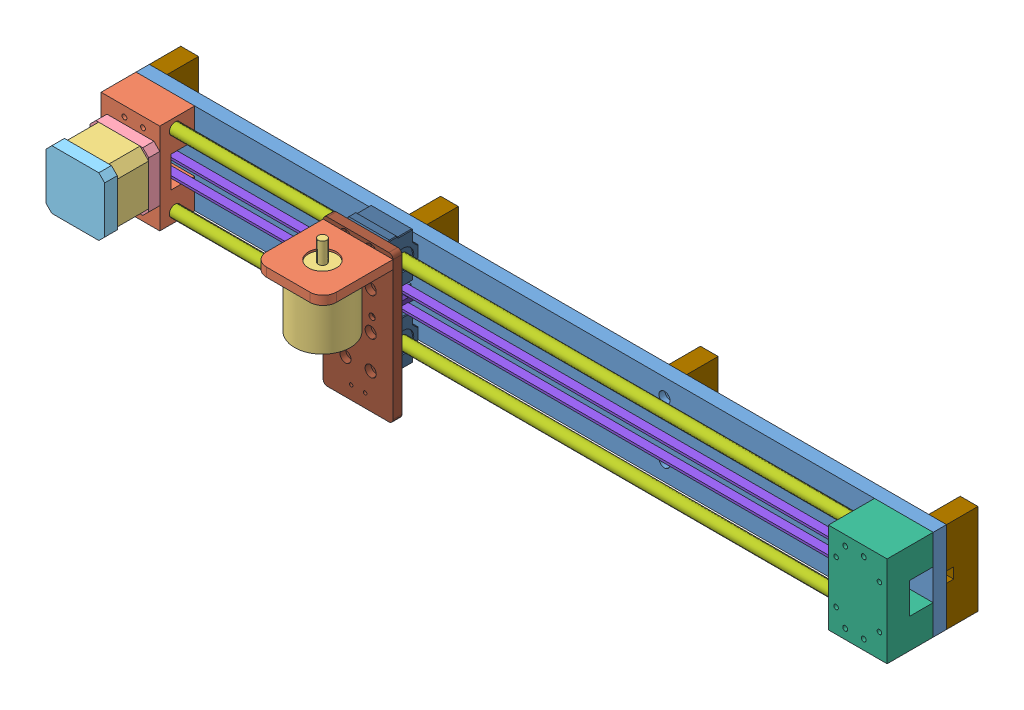
SolidWorks assembly Montagem, configuration Valor predeterminado. Lengths in mm.
Overall size (570.66 115.83 117).
38 component instances, 21 part files, 63 mates.
Components (placement in the parent):
- Base-1: Base [Valor predeterminado] at (-675.4212 -192.8927 563.7125) size (570.47 65 9.53)
- Apoio_guias-1: Apoio_guias [Valor predeterminado] at (-675.4212 -192.8927 573.2375) size (42 65 25)
- NEMA_17_STEPPER_ASSEMBLY-1: NEMA_17_STEPPER_ASSEMBLY [Valor predeterminado] at (-686.9212 389.0823 567.6436) x (0 1 0) z (0 0 1) size (42 42.19 62.3)
  - STEPPER_PART_2-1: STEPPER_PART_2 [Valor predeterminado] at (-549.475 -32.5 22.825) x (0 -1 0) z (0 0 1) size (42 42 22.3)
  - STEPPER_PART_3-1: STEPPER_PART_3 [Valor predeterminado] at (-549.475 -32.5 30.525) x (0 -1 0) z (0 0 1) size (42 42 31)
  - STEPPER_PART_1-1: STEPPER_PART_1 [Valor predeterminado] at (-549.475 -32.3132 22.825) x (0 -1 0) z (0 0 1) size (42 42 9)
- Apoio_guias_sem_motor-1: Apoio_guias_sem_motor [Valor predeterminado] at (-104.9462 -127.8927 573.2375) x (-1 0 0) z (0 0 1) size (42 65 33)
- Barra_redonda_8mm-1: Barra_redonda_8mm [Valor predeterminado] at (-641.4212 -185.8927 587.2375) x (0 -0.043617 -0.999048) z (1 0 0) size (8.16 8.16 502.48)
- Barra_redonda_8mm-2: Barra_redonda_8mm [Valor predeterminado] at (-641.4212 -134.8927 587.2375) x (0 -0.862765 -0.505605) z (1 0 0) size (8.16 8.16 502.48)
- Correia-1: Correia [Valor predeterminado] at (-654.4212 -160.3927 581.285) size (541.47 13 6.25)
- Pe-1: Pe [Valor predeterminado] at (-675.4212 -192.8927 541.1877) size (12.7 65 22.52)
- Pe-2: Pe [Valor predeterminado] at (-489.4962 -192.8927 541.1877) size (12.7 65 22.52)
- Pe-3: Pe [Valor predeterminado] at (-303.5712 -192.8927 541.1877) size (12.7 65 22.52)
- Pe-4: Pe [Valor predeterminado] at (-117.6462 -192.8927 541.1877) size (12.7 65 22.52)
- Rolamento linear-1: Rolamento linear [Valor predeterminado] at (-470.1504 -134.9863 589.5561) x (0 1 0) z (-1 0 0) size (34 22 30)
- Rolamento linear-2: Rolamento linear [Valor predeterminado] at (-470.1504 -185.9863 589.5561) x (0 1 0) z (-1 0 0) size (34 22 30)
- Mesa_móvel-1: Mesa_móvel [Valor predeterminado] at (-497.1504 -117.8927 598.2375) x (0 -1 0) z (0 0 1) size (105 50 6.35)
- Barra_5mm-2: Barra_5mm [Valor predeterminado] at (-125.9462 -160.3927 574.2375) x (0.889125 0.457665 0) z (0 0 1) size (5 5 28)
- Rolamento_5mm-4: Rolamento_5mm [Valor predeterminado] at (423.5288 -127.8927 584.7125) size (11 11 4)
  - 5MM_BEARING_COVER-1: 5MM_BEARING_COVER [Valor predeterminado] at (-549.475 -32.5 9.525) x (1 0 0) z (0 0 -1) size (10 10 4)
  - 5MM_BEARING_INNER_RACE-1: 5MM_BEARING_INNER_RACE [Valor predeterminado] at (-549.475 -32.5 5.525) size (6 6 4)
  - 5MM_BEARING_OUTER_RACE-1: 5MM_BEARING_OUTER_RACE [Valor predeterminado] at (-549.475 -32.5 5.525) size (11 11 4)
- Rolamento_5mm-5: Rolamento_5mm [Valor predeterminado] at (423.5288 -127.8927 592.7125) size (11 11 4)
  - 5MM_BEARING_COVER-1: 5MM_BEARING_COVER [Valor predeterminado] at (-549.475 -32.5 9.525) x (1 0 0) z (0 0 -1) size (10 10 4)
  - 5MM_BEARING_INNER_RACE-1: 5MM_BEARING_INNER_RACE [Valor predeterminado] at (-549.475 -32.5 5.525) size (6 6 4)
  - 5MM_BEARING_OUTER_RACE-1: 5MM_BEARING_OUTER_RACE [Valor predeterminado] at (-549.475 -32.5 5.525) size (11 11 4)
- Rolamento_5mm-6: Rolamento_5mm [Valor predeterminado] at (421.9067 -213.6492 588.7125) x (0.987859 -0.155352 0) z (0 0 1) size (11 11 4)
  - 5MM_BEARING_COVER-1: 5MM_BEARING_COVER [Valor predeterminado] at (-549.475 -32.5 9.525) x (1 0 0) z (0 0 -1) size (10 10 4)
  - 5MM_BEARING_INNER_RACE-1: 5MM_BEARING_INNER_RACE [Valor predeterminado] at (-549.475 -32.5 5.525) size (6 6 4)
  - 5MM_BEARING_OUTER_RACE-1: 5MM_BEARING_OUTER_RACE [Valor predeterminado] at (-549.475 -32.5 5.525) size (11 11 4)
- Suporte cabos-1: Suporte cabos [Valor predeterminado] at (-675.4212 -192.8927 541.1877) size (12.7 30 22.52)
- Presilha_correia1-1: Presilha_correia1 [Valor predeterminado] at (-497.6504 -165.7487 576.2375) size (25 4 22)
- Polia-4: Polia [Valor predeterminado] at (-654.4212 -160.3927 574.765) x (0 0 1) z (-0.974978 -0.222303 0) size (14.1 13 13)
- Polia-5: Polia [Valor predeterminado] at (-125.9462 -160.3927 574.765) x (0 0 1) z (-0.665772 0.746155 0) size (14.1 13 13)
- Presilha_correia2-1: Presilha_correia2 [Valor predeterminado] at (-494.6504 -161.7487 592.4825) x (1 0 0) z (0 1 0) size (5 16.24 4.06)
- Presilha_correia2-2: Presilha_correia2 [Valor predeterminado] at (-480.6504 -157.6847 576.2375) x (1 0 0) z (0 -1 0) size (5 16.24 4.06)
- Suporte encoder-1: Suporte encoder [Valor predeterminado] at (-497.1504 -120.7177 604.5875) x (1 0 0) z (0 -1 0) size (50 50 6.35)
- Encoder-1: Encoder [Valor predeterminado] at (-485.1504 -165.0677 630.0875) x (-0.622939 0 0.78227) z (0.78227 0 0.622939) size (40 58 40)
Mates (geometry in assembly coordinates):
- Concêntrico1: concentric aligned: cylinder of Base-1 through (-658.7212 -134.8927 563.7125) axis (0 0 -1) radius 2.2479; cylinder of Apoio_guias-1 through (-658.7212 -134.8927 573.2375) axis (0 0 -1) radius 1.7272
- Concêntrico2: concentric aligned: cylinder of Base-1 through (-658.7212 -185.8927 563.7125) axis (0 0 -1) radius 2.2479; cylinder of Apoio_guias-1 through (-658.7212 -185.8927 573.2375) axis (0 0 -1) radius 1.7272
- Concêntrico5: concentric aligned: cylinder of Apoio_guias-1 through (-669.9212 -144.8927 573.2375) axis (0 0 -1) radius 1.6; cylinder of NEMA_17_STEPPER_ASSEMBLY-1/STEPPER_PART_3-1 through (-669.9212 -144.8927 598.1686) axis (0 0 -1) radius 1.5
- Coincidente3: coincident anti-aligned: plane of Base-1 through (-675.4212 -192.8927 573.2375) normal (0 0 1); plane of Apoio_guias-1 through (-675.4212 -192.8927 573.2375) normal (0 0 -1)
- Concêntrico10: concentric aligned: cylinder of Base-1 through (-134.9462 -185.8927 563.7125) axis (0 0 -1) radius 2.2479; cylinder of Apoio_guias_sem_motor-1 through (-134.9462 -185.8927 573.2375) axis (0 0 -1) radius 1.7272
- Concêntrico11: concentric aligned: cylinder of Base-1 through (-134.9462 -134.8927 563.7125) axis (0 0 -1) radius 2.2479; cylinder of Apoio_guias_sem_motor-1 through (-134.9462 -134.8927 573.2375) axis (0 0 -1) radius 1.7272
- Coincidente6: coincident anti-aligned: plane of Base-1 through (-675.4212 -192.8927 573.2375) normal (0 0 1); plane of Apoio_guias_sem_motor-1 through (-104.9462 -127.8927 573.2375) normal (0 0 -1)
- Concêntrico17: concentric anti-aligned: cylinder of Apoio_guias-1 through (-633.4212 -185.8927 587.2375) axis (1 0 0) radius 4.1672; cylinder of Barra_redonda_8mm-1 through (-138.9412 -185.8927 587.2375) axis (-1 0 0) radius 4.0802
- Concêntrico18: concentric anti-aligned: cylinder of Apoio_guias-1 through (-633.4212 -134.8927 587.2375) axis (1 0 0) radius 4.1672; cylinder of Barra_redonda_8mm-2 through (-138.9412 -134.8927 587.2375) axis (-1 0 0) radius 4.0802
- Coincidente18: coincident anti-aligned: plane of Apoio_guias-1 through (-641.4212 -185.8927 587.2375) normal (1 0 0); plane of Barra_redonda_8mm-1 through (-641.4212 -185.8927 587.2375) normal (-1 0 0)
- Coincidente19: coincident anti-aligned: plane of Apoio_guias-1 through (-641.4212 -134.8927 587.2375) normal (1 0 0); plane of Barra_redonda_8mm-2 through (-641.4212 -134.8927 587.2375) normal (-1 0 0)
- Coincidente29: coincident anti-aligned: plane of Base-1 through (-675.4212 -192.8927 563.7125) normal (0 0 -1); plane of Pe-4 through (-117.6462 -127.8927 563.7125) normal (0 0 1)
- Coincidente30: coincident anti-aligned: plane of Base-1 through (-675.4212 -192.8927 563.7125) normal (0 0 -1); plane of Pe-3 through (-303.5712 -127.8927 563.7125) normal (0 0 1)
- Coincidente31: coincident anti-aligned: plane of Base-1 through (-675.4212 -192.8927 563.7125) normal (0 0 -1); plane of Pe-2 through (-489.4962 -127.8927 563.7125) normal (0 0 1)
- Concêntrico24: concentric anti-aligned: cylinder of Base-1 through (-111.2962 -180.1927 573.2375) axis (0 0 1) radius 2.2479; cylinder of Pe-4 through (-111.2962 -180.1927 541.1877) axis (0 0 -1) radius 1.7272
- Concêntrico25: concentric anti-aligned: cylinder of Base-1 through (-297.2212 -180.1927 573.2375) axis (0 0 1) radius 2.2479; cylinder of Pe-3 through (-297.2212 -180.1927 541.1877) axis (0 0 -1) radius 1.7272
- Concêntrico26: concentric anti-aligned: cylinder of Base-1 through (-297.2212 -140.5927 573.2375) axis (0 0 1) radius 2.2479; cylinder of Pe-3 through (-297.2212 -140.5927 541.1877) axis (0 0 -1) radius 1.7272
- Concêntrico27: concentric anti-aligned: cylinder of Base-1 through (-111.2962 -140.5927 573.2375) axis (0 0 1) radius 2.2479; cylinder of Pe-4 through (-111.2962 -140.5927 541.1877) axis (0 0 -1) radius 1.7272
- Concêntrico28: concentric anti-aligned: cylinder of Base-1 through (-483.1462 -180.1927 573.2375) axis (0 0 1) radius 2.2479; cylinder of Pe-2 through (-483.1462 -180.1927 541.1877) axis (0 0 -1) radius 1.7272
- Concêntrico29: concentric anti-aligned: cylinder of Base-1 through (-483.1462 -140.5927 573.2375) axis (0 0 1) radius 2.2479; cylinder of Pe-2 through (-483.1462 -140.5927 541.1877) axis (0 0 -1) radius 1.7272
- Concêntrico30: concentric anti-aligned: cylinder of Barra_redonda_8mm-2 through (-138.9412 -134.8927 587.2375) axis (-1 0 0) radius 4.0802; cylinder of Rolamento linear-1 through (-500.1504 -134.8927 587.2375) axis (1 0 0) radius 4.025
- Concêntrico31: concentric anti-aligned: cylinder of Barra_redonda_8mm-1 through (-138.9412 -185.8927 587.2375) axis (-1 0 0) radius 4.0802; cylinder of Rolamento linear-2 through (-500.1504 -185.8927 587.2375) axis (1 0 0) radius 4.025
- Concêntrico36: concentric aligned: cylinder of Rolamento linear-1 through (-476.1504 -122.8927 598.2375) axis (0 0 1) radius 2; cylinder of Mesa_móvel-1 through (-476.1504 -122.8927 604.5875) axis (0 0 1) radius 2.15
- Concêntrico38: concentric anti-aligned: cylinder of Rolamento linear-1 through (-494.1504 -122.8927 580.2375) axis (0 0 -1) radius 2; cylinder of Mesa_móvel-1 through (-494.1504 -122.8927 604.5875) axis (0 0 1) radius 2.15
- Concêntrico39: concentric aligned: cylinder of Rolamento linear-2 through (-476.1504 -173.8927 598.2375) axis (0 0 1) radius 2; cylinder of Mesa_móvel-1 through (-476.1504 -173.8927 604.5875) axis (0 0 1) radius 2.15
- Concêntrico40: concentric anti-aligned: cylinder of Rolamento linear-2 through (-494.1504 -173.8927 580.2375) axis (0 0 -1) radius 2; cylinder of Mesa_móvel-1 through (-494.1504 -173.8927 604.5875) axis (0 0 1) radius 2.15
- Coincidente32: coincident anti-aligned: plane of Rolamento linear-1 through (-470.1504 -134.9863 598.2375) normal (0 0 1); plane of Mesa_móvel-1 through (-497.1504 -117.8927 598.2375) normal (0 0 -1)
- Concêntrico41: concentric aligned: cylinder of Apoio_guias-1 through (-654.4212 -160.3927 594.2375) axis (0 0 1) radius 11.1125; cylinder of NEMA_17_STEPPER_ASSEMBLY-1/STEPPER_PART_3-1 through (-654.4212 -160.3927 596.1686) axis (0 0 1) radius 11
- Concêntrico43: concentric aligned: cylinder of Rolamento_5mm-4/5MM_BEARING_INNER_RACE-1 through (-125.9462 -160.3927 594.2375) axis (0 0 -1) radius 2.5; cylinder of Rolamento_5mm-5/5MM_BEARING_INNER_RACE-1 through (-125.9462 -160.3927 602.2375) axis (0 0 -1) radius 2.5
- Concêntrico44: concentric aligned: cylinder of Rolamento_5mm-5/5MM_BEARING_INNER_RACE-1 through (-125.9462 -160.3927 602.2375) axis (0 0 -1) radius 2.5; cylinder of Rolamento_5mm-6/5MM_BEARING_INNER_RACE-1 through (-125.9462 -160.3927 598.2375) axis (0 0 -1) radius 2.5
- Coincidente33: coincident anti-aligned: plane of Rolamento_5mm-4/5MM_BEARING_OUTER_RACE-1 through (-125.9462 -160.3927 594.2375) normal (0 0 1); plane of Rolamento_5mm-6/5MM_BEARING_OUTER_RACE-1 through (-125.9462 -160.3927 594.2375) normal (0 0 -1)
- Coincidente34: coincident anti-aligned: plane of Rolamento_5mm-5/5MM_BEARING_OUTER_RACE-1 through (-125.9462 -160.3927 598.2375) normal (0 0 -1); plane of Rolamento_5mm-6/5MM_BEARING_OUTER_RACE-1 through (-125.9462 -160.3927 598.2375) normal (0 0 1)
- Concêntrico45: concentric aligned: cylinder of Barra_5mm-2 through (-125.9462 -160.3927 602.2375) axis (0 0 -1) radius 2.5; cylinder of Rolamento_5mm-5/5MM_BEARING_INNER_RACE-1 through (-125.9462 -160.3927 602.2375) axis (0 0 -1) radius 2.5
- Coincidente35: coincident aligned: plane of Barra_5mm-2 through (-123.7234 -159.2485 602.2375) normal (0 0 1); plane of Rolamento_5mm-5/5MM_BEARING_INNER_RACE-1 through (-125.9462 -160.3927 602.2375) normal (0 0 1)
- Concêntrico46: concentric anti-aligned: cylinder of Apoio_guias_sem_motor-1 through (-125.9462 -160.3927 590.2375) axis (0 0 1) radius 5.5; cylinder of Rolamento_5mm-5/5MM_BEARING_OUTER_RACE-1 through (-125.9462 -160.3927 602.2375) axis (0 0 -1) radius 5.5
- Coincidente36: coincident anti-aligned: plane of Apoio_guias_sem_motor-1 through (-125.9462 -160.3927 602.2375) normal (0 0 -1); plane of Rolamento_5mm-5/5MM_BEARING_OUTER_RACE-1 through (-125.9462 -160.3927 602.2375) normal (0 0 1)
- Concêntrico48: concentric anti-aligned: cylinder of Base-1 through (-669.0712 -140.5927 573.2375) axis (0 0 1) radius 2.2479; cylinder of Pe-1 through (-669.0712 -140.5927 541.1877) axis (0 0 -1) radius 1.7272
- Concêntrico49: concentric anti-aligned: cylinder of Base-1 through (-669.0712 -180.1927 573.2375) axis (0 0 1) radius 2.2479; cylinder of Pe-1 through (-669.0712 -180.1927 541.1877) axis (0 0 -1) radius 1.7272
- Coincidente41: coincident anti-aligned: plane of Base-1 through (-675.4212 -192.8927 563.7125) normal (0 0 -1); plane of Pe-1 through (-675.4212 -127.8927 563.7125) normal (0 0 1)
- Coincidente44: coincident anti-aligned: plane of Pe-1 through (-675.4212 -192.8927 563.7125) normal (0 -1 0); plane of Suporte cabos-1 through (-662.7212 -192.8927 563.7125) normal (0 1 0)
- Coincidente45: coincident aligned: plane of Pe-1 through (-675.4212 -192.8927 541.1877) normal (-1 0 0); plane of Suporte cabos-1 through (-675.4212 -192.8927 541.1877) normal (-1 0 0)
- Coincidente46: coincident aligned: plane of Pe-1 through (-675.4212 -192.8927 541.1877) normal (0 0 -1); plane of Suporte cabos-1 through (-662.7212 -192.8927 541.1877) normal (0 0 -1)
- Concêntrico50: concentric anti-aligned: cylinder of Mesa_móvel-1 through (-475.1504 -163.7487 604.5875) axis (0 0 1) radius 2.2; cylinder of Presilha_correia1-1 through (-475.1504 -163.7487 576.2375) axis (0 0 -1) radius 0.889
- Concêntrico51: concentric anti-aligned: cylinder of Mesa_móvel-1 through (-495.1504 -163.7487 604.5875) axis (0 0 1) radius 2.2; cylinder of Presilha_correia1-1 through (-495.1504 -163.7487 576.2375) axis (0 0 -1) radius 0.889
- Coincidente47: coincident anti-aligned: plane of Mesa_móvel-1 through (-497.1504 -117.8927 598.2375) normal (0 0 -1); plane of Presilha_correia1-1 through (-472.6504 -161.7487 598.2375) normal (0 0 1)
- Concêntrico53: concentric aligned: cylinder of Correia-1 through (-654.4212 -160.3927 581.285) axis (0 0 1) radius 4.848; cylinder of Polia-4 through (-654.4212 -160.3927 580.935) axis (0 0 1) radius 4.84
- Distância10: distance = 0.4 mm anti-aligned: plane of Correia-1 through (-125.9462 -160.3927 587.535) normal (0 0 1); plane of Polia-4 through (-654.4212 -160.3927 587.935) normal (0 0 -1)
- Concêntrico54: concentric aligned: cylinder of NEMA_17_STEPPER_ASSEMBLY-1/STEPPER_PART_3-1 through (-654.4212 -160.3927 575.1686) axis (0 0 1) radius 2.5; cylinder of Polia-4 through (-654.4212 -160.3927 588.865) axis (0 0 1) radius 2.5
- Concêntrico56: concentric anti-aligned: cylinder of Barra_5mm-2 through (-125.9462 -160.3927 602.2375) axis (0 0 -1) radius 2.5; cylinder of Polia-5 through (-125.9462 -160.3927 588.865) axis (0 0 1) radius 2.5
- Distância11: distance = 0.4 mm anti-aligned: plane of Correia-1 through (-125.9462 -160.3927 587.535) normal (0 0 1); plane of Polia-5 through (-125.9462 -160.3927 587.935) normal (0 0 -1)
- Concêntrico57: concentric aligned: cylinder of Correia-1 through (-125.9462 -160.3927 581.285) axis (0 0 1) radius 4.848; cylinder of Polia-5 through (-125.9462 -160.3927 580.935) axis (0 0 1) radius 4.84
- Coincidente53: coincident anti-aligned: plane of Correia-1 through (-125.9462 -160.3927 587.535) normal (0 0 1); plane of Presilha_correia1-1 through (-497.6504 -161.7487 587.535) normal (0 0 -1)
- Concêntrico58: concentric aligned: cylinder of Presilha_correia1-1 through (-478.1504 -165.7487 589.86) axis (0 -1 0) radius 1.2192; cylinder of Presilha_correia2-2 through (-478.1504 -157.6847 589.86) axis (0 -1 0) radius 0.889
- Concêntrico59: concentric aligned: cylinder of Presilha_correia1-1 through (-478.1504 -165.7487 578.86) axis (0 -1 0) radius 1.2192; cylinder of Presilha_correia2-2 through (-478.1504 -157.6847 578.86) axis (0 -1 0) radius 0.889
- Concêntrico60: concentric anti-aligned: cylinder of Presilha_correia1-1 through (-492.1504 -165.7487 589.86) axis (0 -1 0) radius 1.2192; cylinder of Presilha_correia2-1 through (-492.1504 -161.7487 589.86) axis (0 1 0) radius 0.889
- Concêntrico61: concentric anti-aligned: cylinder of Presilha_correia1-1 through (-492.1504 -165.7487 578.86) axis (0 -1 0) radius 1.2192; cylinder of Presilha_correia2-1 through (-492.1504 -161.7487 578.86) axis (0 1 0) radius 0.889
- Coincidente54: coincident anti-aligned: plane of Presilha_correia1-1 through (-497.6504 -161.7487 576.2375) normal (0 1 0); plane of Presilha_correia2-1 through (-494.6504 -161.7487 592.4825) normal (0 -1 0)
- Coincidente55: coincident anti-aligned: plane of Presilha_correia1-1 through (-497.6504 -161.7487 576.2375) normal (0 1 0); plane of Presilha_correia2-2 through (-480.6504 -161.7487 576.2375) normal (0 -1 0)
- Concêntrico63: concentric aligned: cylinder of Mesa_móvel-1 through (-502.6504 -123.8927 598.2375) axis (0 0 -1) radius 2.15; cylinder of Suporte encoder-1 through (-502.6504 -123.8927 604.5875) axis (0 0 -1) radius 1.65
- Concêntrico64: concentric aligned: cylinder of Mesa_móvel-1 through (-467.6504 -123.8927 598.2375) axis (0 0 -1) radius 2.15; cylinder of Suporte encoder-1 through (-467.6504 -123.8927 604.5875) axis (0 0 -1) radius 1.65
- Coincidente56: coincident anti-aligned: plane of Mesa_móvel-1 through (-497.1504 -117.8927 604.5875) normal (0 0 1); plane of Suporte encoder-1 through (-510.1504 -120.7177 604.5875) normal (0 0 -1)
- Concêntrico65: concentric anti-aligned: cylinder of Suporte encoder-1 through (-485.1504 -120.7177 630.0875) axis (0 1 0) radius 10; cylinder of Encoder-1 through (-485.1504 -122.0677 630.0875) axis (0 -1 0) radius 10
- Coincidente57: coincident anti-aligned: plane of Suporte encoder-1 through (-497.1504 -127.0677 604.5875) normal (0 -1 0); plane of Encoder-1 through (-485.1504 -127.0677 630.0875) normal (0 1 0)
